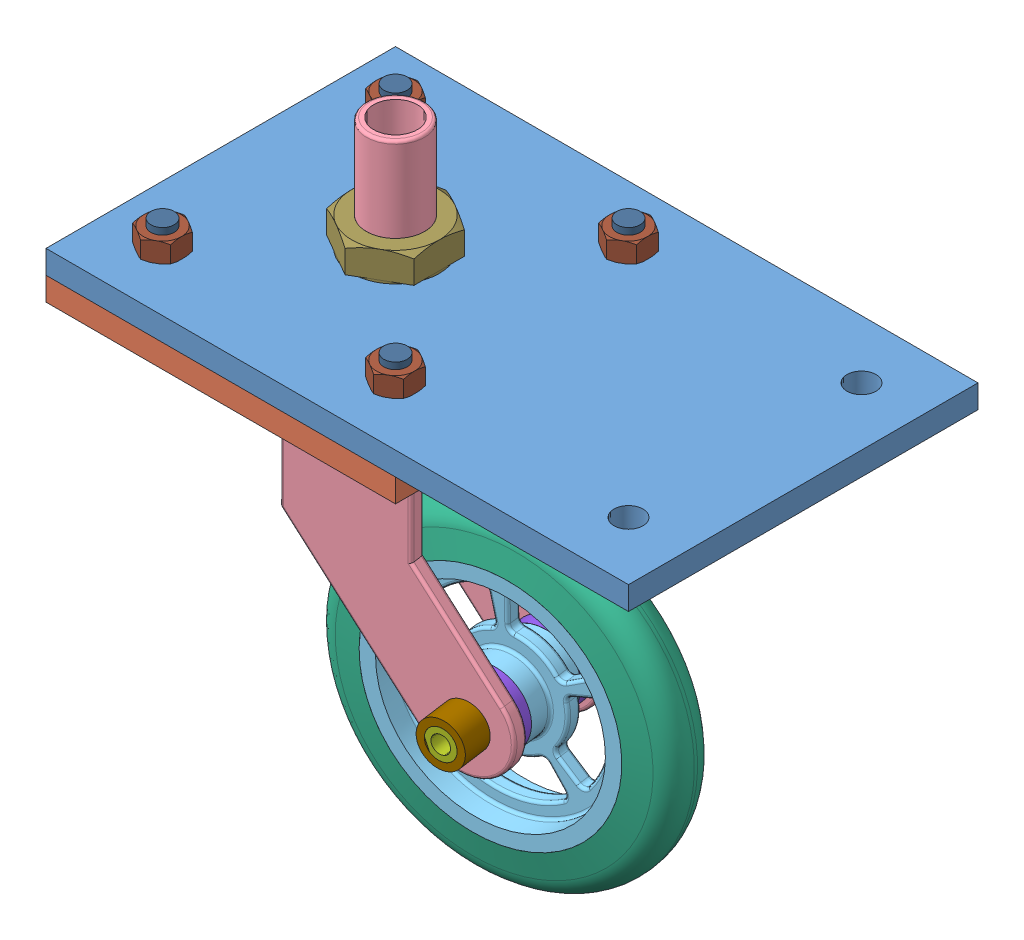
SolidWorks assembly Angled caster assembly, configuration Default. Lengths in mm.
Overall size (200 230.64 120).
23 component instances, 13 part files, 25 mates.
Components (placement in the parent):
- Base.SLDPART.-2: Base.SLDPART. [Default] at (-67.2248 121.9152 -5.3212) size (200 8 120)
- Mount.SLDPART-1: Mount.SLDPART [Default] at (-67.2248 113.9152 -5.3212) x (0 0 -1) z (1 0 0) size (120 8 120)
- Bearing.SLDPART-1: Bearing.SLDPART [Default] at (-67.2248 113.9152 -5.3212) x (-0.156135 0 -0.987736) z (0 -1 0) size (30 30 5)
- Fork.SLDPART-1: Fork.SLDPART [Default] at (-67.2248 108.9152 -5.3212) x (-0.990595 0 0.136828) z (0.136828 0 0.990595) size (91.42 169.11 80)
- Wheel and Axel.2-1: Wheel and Axel.2 [Default] at (-19.8092 90.5639 -35.5079) x (0.136828 0 0.990595) z (0.417494 -0.906848 -0.057667) size (60 115.31 115.31)
  - Wheel.SLDPART-1: Wheel.SLDPART [Default] at (23.415 45.1517 62.4965) size (20 80 80)
  - Tire.SLDPART-1: Tire.SLDPART [Default] at (23.415 45.1517 62.4965) x (1 0 0) z (0 -0.049481 0.998775) size (20 110 110)
  - Axel.SLDPART-1: Axel.SLDPART [Default] at (23.415 45.1517 62.4965) x (0 -0.050219 -0.998738) z (1 0 0) size (10 10 60)
  - Washer.SLDPART-1: Washer.SLDPART [Default] at (8.415 45.1517 62.4965) x (0 -0.153708 -0.988116) z (0 -0.988116 0.153708) size (25 5 25)
  - Washer.SLDPART-2: Washer.SLDPART [Default] at (38.415 45.1517 62.4965) x (0 0.906189 0.422872) z (0 -0.422872 0.906189) size (25 5 25)
- Collar.SLDPART-1: Collar.SLDPART [Default] at (-27.6534 14.8595 14.4503) x (0.371855 -0.926869 -0.051363) z (0.136828 0 0.990595) size (15 15 10)
- Collar.SLDPART-2: Collar.SLDPART [Default] at (-34.4948 14.8595 -35.0795) x (-0.371855 0.926869 0.051363) z (-0.136828 0 -0.990595) size (15 15 10)
- hex screw_am-8: hex screw_am [B18.6.7M - M8 x 1.25 x 25 Indented HHMS --25N] at (-107.2248 107.9152 -45.3212) x (0 1 0) z (-0.004427 0 0.99999) size (31 15.01 13)
- hex nut style 1_am-4: hex nut style 1_am [B18.2.4.1M - Hex nut, Style 1,  M8 x 1.25 --D-N] at (-107.2248 129.8511 -45.3212) x (1 0 0) z (0 -1 0) size (13 15.01 6.8)
- hex nut style 1_am-5: hex nut style 1_am [B18.2.4.1M - Hex nut, Style 1,  M8 x 1.25 --D-N] at (-27.2248 129.8511 -45.3212) x (1 0 0) z (0 -1 0) size (13 15.01 6.8)
- hex nut style 1_am-6: hex nut style 1_am [B18.2.4.1M - Hex nut, Style 1,  M8 x 1.25 --D-N] at (-107.2248 129.8511 34.6788) x (1 0 0) z (0 -1 0) size (13 15.01 6.8)
- hex nut style 1_am-7: hex nut style 1_am [B18.2.4.1M - Hex nut, Style 1,  M8 x 1.25 --D-N] at (-27.2248 129.8511 34.6788) x (1 0 0) z (0 -1 0) size (13 15.01 6.8)
- hex screw_am-9: hex screw_am [B18.6.7M - M8 x 1.25 x 25 Indented HHMS --25N] at (-27.2248 107.9152 -45.3212) x (0 1 0) z (-0.004427 0 0.99999) size (31 15.01 13)
- hex screw_am-10: hex screw_am [B18.6.7M - M8 x 1.25 x 25 Indented HHMS --25N] at (-107.2248 107.9152 34.6788) x (0 1 0) z (-0.004427 0 0.99999) size (31 15.01 13)
- hex screw_am-11: hex screw_am [B18.6.7M - M8 x 1.25 x 25 Indented HHMS --25N] at (-27.2248 107.9152 34.6788) x (0 1 0) z (-0.004427 0 0.99999) size (31 15.01 13)
- hex nut jam_am-3: hex nut jam_am [B18.2.4.5M - Hex jam nut,  M20 x 2.5 --W-N] at (-67.2248 139.9152 -5.3212) x (1 0 0) z (0 1 0) size (30 34.64 10)
- socket set screw flat point_am-11: socket set screw flat point_am [B18.3.6M - M3 x 0.5 x 4 Hex Socket Flat Pt. SS --N] at (-35.4577 11.6687 15.5283) x (0.918151 0.375386 -0.126821) z (0.26968 -0.357539 0.894113) size (4 3 3)
- socket set screw flat point_am-12: socket set screw flat point_am [B18.3.6M - M3 x 0.5 x 4 Hex Socket Flat Pt. SS --N] at (-42.2991 11.6687 -34.0015) x (0.918151 0.375386 -0.126821) z (-0.313249 0.491682 -0.81248) size (4 3 3)
Mates (geometry in assembly coordinates):
- Coincident2: coincident anti-aligned: plane of Base.SLDPART.-2 through (-67.2248 121.9152 -5.3212) normal (0 -1 0); plane of Mount.SLDPART-1 through (-67.2248 121.9152 -5.3212) normal (0 1 0)
- Coincident3: coincident aligned: circle of Base.SLDPART.-2; circle of Mount.SLDPART-1
- Coincident4: coincident aligned: circle of Base.SLDPART.-2; circle of Mount.SLDPART-1
- Coincident5: coincident anti-aligned: plane of Mount.SLDPART-1 through (-67.2248 113.9152 -5.3212) normal (0 -1 0); plane of Bearing.SLDPART-1 through (-67.2248 113.9152 -5.3212) normal (0 1 0)
- Concentric1: concentric anti-aligned: circle of Mount.SLDPART-1; circle of Bearing.SLDPART-1
- Coincident8: coincident anti-aligned: plane of Bearing.SLDPART-1 through (-67.2248 108.9152 -5.3212) normal (0 -1 0); plane of Fork.SLDPART-1 through (-67.2248 108.9152 -5.3212) normal (0 1 0)
- Coincident9: coincident anti-aligned: circle of Bearing.SLDPART-1; circle of Fork.SLDPART-1
- Coincident13: coincident anti-aligned: plane of Fork.SLDPART-1 through (-65.1724 55.9152 9.5377) normal (-0.136828 0 -0.990595); plane of Wheel and Axel.2-1/Washer.SLDPART-2 through (-29.0217 14.8595 4.5443) normal (0.136828 0 0.990595)
- Coincident15: coincident anti-aligned: plane of Fork.SLDPART-1 through (-69.9614 55.9152 -25.1331) normal (-0.136828 0 -0.990595); plane of Collar.SLDPART-2 through (-33.8106 14.8595 -30.1265) normal (0.136828 0 0.990595)
- Parallel4: parallel aligned: plane of Wheel and Axel.2-1/Axel.SLDPART-1 through (-31.0741 14.8595 -10.3146) normal (-0.371855 0.926869 0.051363); plane of Collar.SLDPART-2 through (-34.4948 14.8595 -35.0795) normal (-0.371855 0.926869 0.051363)
- Coincident20: coincident anti-aligned: plane of Fork.SLDPART-1 through (-64.4883 55.9152 14.4907) normal (0.136828 0 0.990595); plane of Collar.SLDPART-1 through (-28.3375 14.8595 9.4973) normal (-0.136828 0 -0.990595)
- Parallel5: parallel anti-aligned: plane of Wheel and Axel.2-1/Axel.SLDPART-1 through (-31.0741 14.8595 -10.3146) normal (-0.371855 0.926869 0.051363); plane of Collar.SLDPART-1 through (-27.6534 14.8595 14.4503) normal (0.371855 -0.926869 -0.051363)
- Concentric6: concentric anti-aligned: cylinder of Mount.SLDPART-1 through (-107.2248 113.9152 -45.3212) axis (0 1 0) radius 5; cylinder of hex screw_am-8 through (-107.2248 82.5152 -45.3212) axis (0 -1 0) radius 4
- Coincident22: coincident anti-aligned: plane of Mount.SLDPART-1 through (-67.2248 113.9152 -5.3212) normal (0 -1 0); plane of hex screw_am-8 through (-111.2248 113.9152 -45.3389) normal (0 1 0)
- Concentric9: concentric aligned: cylinder of hex screw_am-8 through (-107.2248 82.5152 -45.3212) axis (0 -1 0) radius 4; cylinder of hex nut style 1_am-4 through (-107.2248 154.8886 -45.3212) axis (0 -1 0) radius 4
- Concentric12: concentric aligned: cylinder of Base.SLDPART.-2 through (-67.2248 119.9152 -5.3212) axis (0 1 0) radius 12.5; cylinder of hex nut jam_am-3 through (-67.2248 114.8777 -5.3212) axis (0 1 0) radius 10
- Coincident24: coincident anti-aligned: plane of Base.SLDPART.-2 through (-67.2248 129.9152 -5.3212) normal (0 1 0); plane of hex nut jam_am-3 through (-67.2248 129.9152 -22.6417) normal (0 -1 0)
- Coincident26: coincident anti-aligned: plane of Wheel and Axel.2-1/Axel.SLDPART-1 through (-33.2797 15.1903 10.1799) normal (-0.918151 -0.375386 0.126821); plane of socket set screw flat point_am-11 through (-32.0754 14.0254 15.4505) normal (0.918151 0.375386 -0.126821)
- Concentric164: concentric anti-aligned: cylinder of Collar.SLDPART-1 through (-34.5405 12.0437 15.4016) axis (0.918151 0.375386 -0.126821) radius 1.5; cylinder of socket set screw flat point_am-11 through (-47.1182 6.9013 17.1389) axis (-0.918151 -0.375386 0.126821) radius 1.5
- Coincident27: coincident anti-aligned: plane of Wheel and Axel.2-1/Axel.SLDPART-1 through (-38.7528 15.1903 -29.4439) normal (-0.918151 -0.375386 0.126821); plane of socket set screw flat point_am-12 through (-38.3838 12.3845 -35.0778) normal (0.918151 0.375386 -0.126821)
- Concentric165: concentric anti-aligned: cylinder of Collar.SLDPART-2 through (-41.3818 12.0437 -34.1282) axis (0.918151 0.375386 -0.126821) radius 1.5; cylinder of socket set screw flat point_am-12 through (-53.9596 6.9013 -32.3909) axis (-0.918151 -0.375386 0.126821) radius 1.5
- Coincident28: coincident anti-aligned: plane of Fork.SLDPART-1 through (-65.1724 55.9152 9.5377) normal (-0.136828 0 -0.990595); plane of Wheel and Axel.2-1/Washer.SLDPART-2 through (-29.0217 14.8595 4.5443) normal (0.136828 0 0.990595)
- Concentric166: concentric aligned: cylinder of Fork.SLDPART-1 through (-25.601 14.8595 29.3092) axis (-0.136828 0 -0.990595) radius 5; cylinder of Wheel and Axel.2-1/Axel.SLDPART-1 through (-26.9693 14.8595 19.4033) axis (-0.136828 0 -0.990595) radius 5
- Concentric167: concentric anti-aligned: cylinder of Wheel and Axel.2-1/Axel.SLDPART-1 through (-26.9693 14.8595 19.4033) axis (-0.136828 0 -0.990595) radius 5; cylinder of Collar.SLDPART-2 through (-35.1789 14.8595 -40.0324) axis (0.136828 0 0.990595) radius 5
- Concentric168: concentric aligned: cylinder of Wheel and Axel.2-1/Axel.SLDPART-1 through (-26.9693 14.8595 19.4033) axis (-0.136828 0 -0.990595) radius 5; cylinder of Collar.SLDPART-1 through (-26.9693 14.8595 19.4033) axis (-0.136828 0 -0.990595) radius 5
